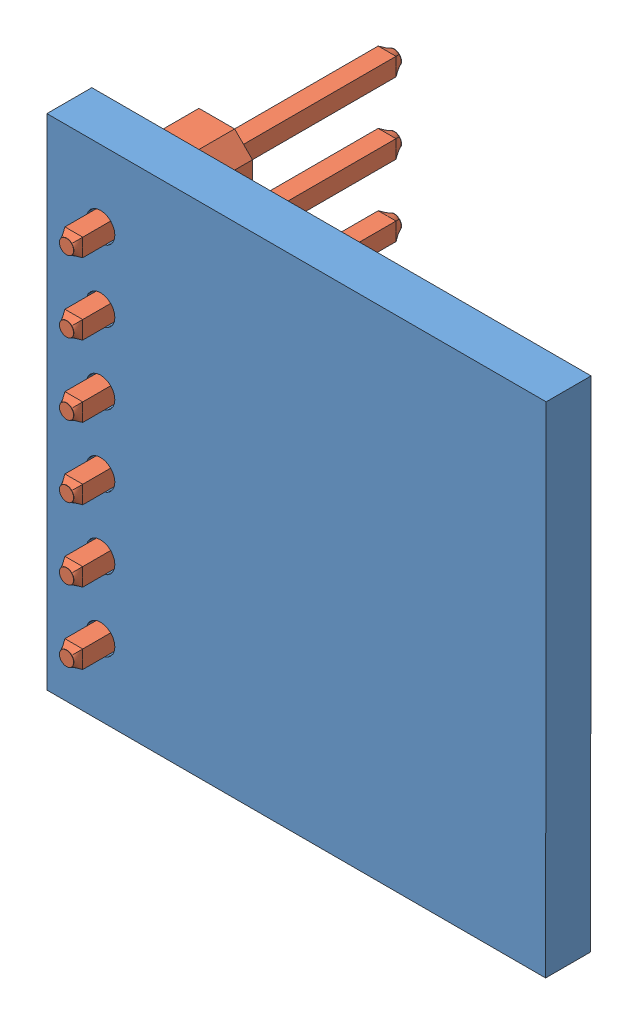
SolidWorks assembly SparkFun ADXL335 Triple Axis Accelerometer Breakout SEN-09269, configuration Default. Lengths in mm.
Overall size (17.78 17.78 11.76).
8 component instances, 2 part files, 3 mates.
Components (placement in the parent):
- adxl335_v13-1: adxl335_v13 [Default] at origin size (17.78 17.78 1.6)
- Male Header 6 Pin-1: Male Header 6 Pin [Default] at (52.988 -3.8842 -25.6151) size (2.54 15.24 11.76)
  - Male Header Pin-1: Male Header Pin [Default] at (-51.078 6.4242 23.0751) size (2.54 2.54 11.76)
  - Male Header Pin-2: Male Header Pin [Default] at (-51.078 8.9642 23.0751) size (2.54 2.54 11.76)
  - Male Header Pin-3: Male Header Pin [Default] at (-51.078 11.5042 23.0751) size (2.54 2.54 11.76)
  - Male Header Pin-4: Male Header Pin [Default] at (-51.078 14.0442 23.0751) size (2.54 2.54 11.76)
  - Male Header Pin-5: Male Header Pin [Default] at (-51.078 16.5842 23.0751) size (2.54 2.54 11.76)
  - Male Header Pin-6: Male Header Pin [Default] at (-51.078 19.1242 23.0751) size (2.54 2.54 11.76)
Mates (geometry in assembly coordinates):
- Coincident1: coincident: plane of adxl335_v13-1 through (0 0 0) normal (0 0 -1); plane of Male Header 6 Pin-1/Male Header Pin-6 through (3.18 16.51 0) normal (0 0 1)
- Concentric1: concentric: cylinder of adxl335_v13-1 through (1.91 15.24 1.6) axis (0 0 -1) radius 0.51; cylinder of Male Header 6 Pin-1/Male Header Pin-6 through (1.91 15.24 2.812) axis (0 0 -1) radius 0.254
- Concentric2: concentric aligned: cylinder of adxl335_v13-1 through (1.91 2.54 1.6) axis (0 0 -1) radius 0.51; cylinder of Male Header 6 Pin-1/Male Header Pin-1 through (1.91 2.54 2.812) axis (0 0 -1) radius 0.254
